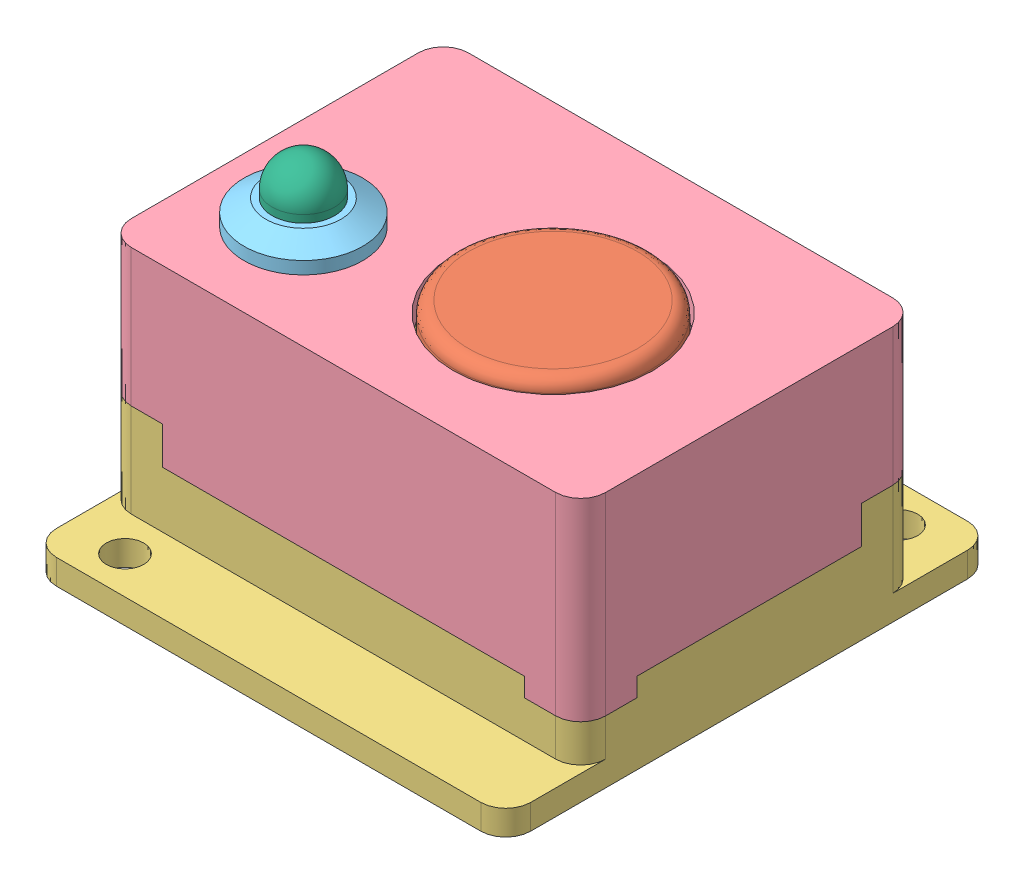
SolidWorks assembly Conjunto_sensor, configuration Default. Lengths in mm.
Overall size (38 25.6 39).
8 component instances, 7 part files, 11 mates.
Components (placement in the parent):
- Placa-1: Placa [Default] at (0.0753 1.0047 -1.4363) x (0 0 -1) z (-1 0 0) size (19.9 1.5 22.1)
- Sensor-1: Sensor [Default] at (0.0753 1.9047 -0.3263) x (0 0 1) z (-1 0 0) size (15.5 18 15.5)
- Base-1: Base [Default] at (-4.3747 -5.4953 -1.4863) size (38 9.5 39)
- Tampa2-1: Tampa2 [Default] at (-4.3747 13.0047 -1.4863) x (1 0 0) z (0 0 -1) size (38 15.5 27)
- LED_8mm-1: LED_8mm [Default] at (-16.7253 10.1557 0.0871) size (9.5 23.85 9.5)
  - Suporte_LED-1: Suporte_LED [Default] at (0.8006 -5.901 3.5866) size (9.5 12.75 9.5)
  - LED-1: LED [Default] at (0.8006 7.449 3.5866) size (5 3.1 5)
  - Conexao-1: Conexao [Default] at (0.8006 -7.901 3.5866) x (0.063421 0 0.997987) z (-0.997987 0 0.063421) size (8 8 8)
Mates (geometry in assembly coordinates):
- Concentric2: concentric anti-aligned: cylinder of Placa-1 through (0.0753 -0.4953 4.6737) axis (0 -1 0) radius 0.625; cylinder of Sensor-1 through (0.0753 -2.0953 4.6737) axis (0 1 0) radius 0.6
- Concentric3: concentric anti-aligned: cylinder of Placa-1 through (0.0753 -0.4953 -5.3263) axis (0 -1 0) radius 0.625; cylinder of Sensor-1 through (0.0753 -2.0953 -5.3263) axis (0 1 0) radius 0.6
- Distance1: distance = 16.4 mm anti-aligned: plane of Placa-1 through (-10.9747 -0.4953 8.5137) normal (0 -1 0); plane of Sensor-1 through (0.0753 15.9047 -0.3263) normal (0 1 0)
- Coincident2: coincident anti-aligned: plane of Placa-1 through (-10.9747 -0.4953 8.5137) normal (0 -1 0); plane of Base-1 through (-23.3747 -0.4953 12.0137) normal (0 1 0)
- Coincident4: coincident anti-aligned: plane of Base-1 through (14.6253 1.0047 12.0137) normal (0 1 0); plane of Tampa2-1 through (14.6253 1.0047 -14.9863) normal (0 -1 0)
- Coincident5: coincident anti-aligned: plane of Base-1 through (-18.8747 4.0047 9.5137) normal (1 0 0); plane of Tampa2-1 through (-18.8747 4.0047 9.5137) normal (-1 0 0)
- Coincident6: coincident anti-aligned: plane of Base-1 through (-20.8747 -0.4953 -10.4863) normal (0 0 -1); plane of Tampa2-1 through (-20.8747 -0.4953 -10.4863) normal (0 0 1)
- Concentric6: concentric anti-aligned: cylinder of Tampa2-1 through (-15.9247 15.0047 3.6737) axis (0 1 0) radius 3.4; cylinder of LED_8mm-1/Suporte_LED-1 through (-15.9247 -19.7568 3.6737) axis (0 -1 0) radius 4
- Coincident7: coincident anti-aligned: plane of Tampa2-1 through (12.6253 15.0047 10.0137) normal (0 1 0); plane of LED_8mm-1/Suporte_LED-1 through (-11.1747 15.0047 3.6737) normal (0 -1 0)
- Concentric7: concentric aligned: cylinder of Placa-1 through (8.5853 -0.4953 5.9737) axis (0 -1 0) radius 1.55; cylinder of Tampa2-1 through (8.5853 1.0047 5.9737) axis (0 -1 0) radius 1.25
- Concentric8: concentric aligned: cylinder of Placa-1 through (-8.4147 -0.4953 -6.6263) axis (0 -1 0) radius 1.55; cylinder of Tampa2-1 through (-8.4147 1.0047 -6.6263) axis (0 -1 0) radius 1.25
